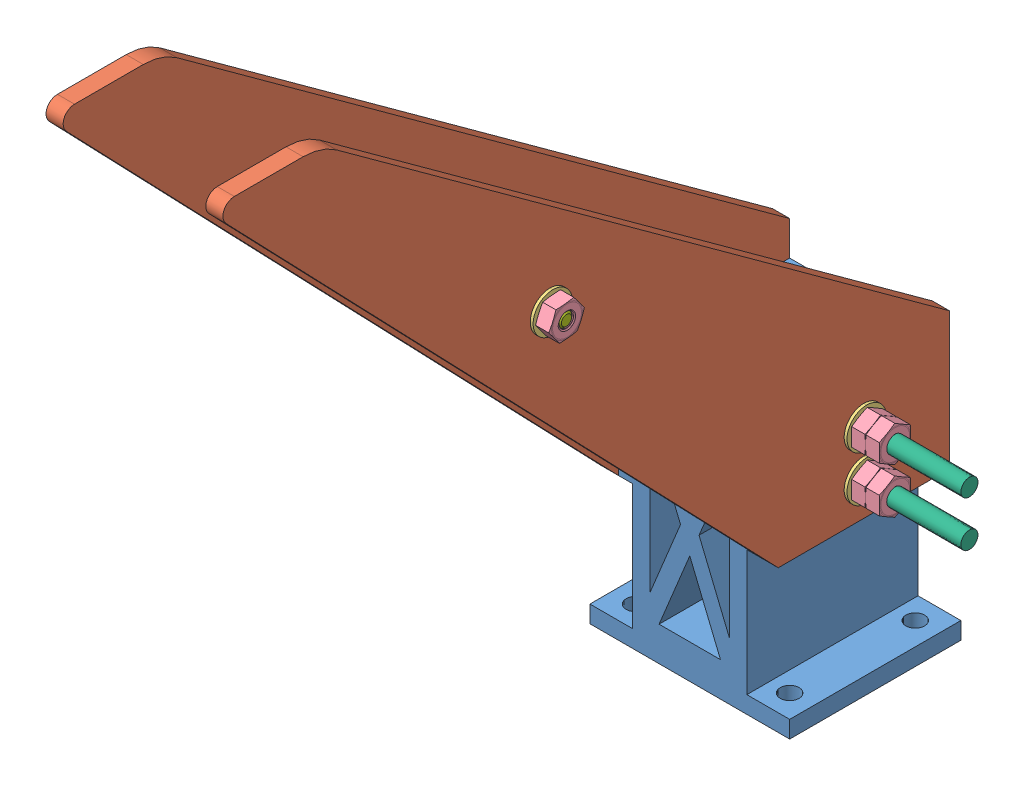
SolidWorks assembly landing gear, configuration Default. Lengths in mm.
Overall size (53 129 127.3).
18 component instances, 7 part files, 29 mates.
Components (placement in the parent):
- landing leg holder-1: landing leg holder [Default] at (5.6883 9.9646 36.397) size (35 43 30)
- landing leg plate-1: landing leg plate [Default] at (-8.3117 45.4646 36.397) x (0 -1 0) z (0 0 1) size (104 3 127.3)
- 9430100-1: 9430100 [Default] at (-10.3117 39.4646 36.397) x (0 -1 0) z (0 0 1) size (6.9 0.5 6.9)
- 9430100-2: 9430100 [Default] at (21.1883 39.4646 36.397) x (0 -1 0) z (0 0 1) size (6.9 0.5 6.9)
- 9430100-3: 9430100 [Default] at (21.1883 47.4646 36.397) x (0 -1 0) z (0 0 1) size (6.9 0.5 6.9)
- 9430100-4: 9430100 [Default] at (-10.3117 47.4646 36.397) x (0 -1 0) z (0 0 1) size (6.9 0.5 6.9)
- M3 Nut-1: M3 Nut [Default] at (25.6883 47.4646 36.397) x (0 0 -1) z (1 0 0) size (5.43 6.27 2.71)
- M3 Nut-2: M3 Nut [Default] at (20.1883 39.4646 36.397) x (0 0 1) z (-1 0 0) size (5.43 6.27 2.71)
- M3 Nut-3: M3 Nut [Default] at (22.6883 39.4646 36.397) x (0 0 1) z (-1 0 0) size (5.43 6.27 2.71)
- M3 Nut-4: M3 Nut [Default] at (22.6883 47.4646 36.397) x (0 0 1) z (-1 0 0) size (5.43 6.27 2.71)
- 9430100-5: 9430100 [Default] at (21.1883 92.4646 91.397) x (0 -1 0) z (0 0 1) size (6.9 0.5 6.9)
- 9430100-6: 9430100 [Default] at (-9.8117 92.4646 91.397) x (0 0.686928 -0.726726) z (0 0.726726 0.686928) size (6.9 0.5 6.9)
- M3x5-1: M3x5 [Default] at (-13.3117 92.4646 91.397) size (8 5.5 5.5)
- M3 Nut-5: M3 Nut [Default] at (20.1883 92.4646 91.397) x (0 -0.993661 -0.112418) z (-1 0 0) size (5.43 6.27 2.71)
- M3x50-1: M3x50 [Default] at (-13.3117 39.4646 36.397) size (53 5.5 5.5)
- M3x50-2: M3x50 [Default] at (-13.3117 47.4646 36.397) x (1 0 0) z (0 -0.610088 0.792334) size (53 5.5 5.5)
- M3 Spacer MF 25mm-1: M3 Spacer MF 25mm [Default] at (17.5844 92.4646 91.397) x (0 0 1) z (-1 0 0) size (5.24 4.54 31.5)
- landing leg plate-3: landing leg plate [Default] at (19.6883 45.4646 36.397) x (0 -1 0) z (0 0 1) size (104 3 127.3)
Mates (geometry in assembly coordinates):
- Coincident9: coincident anti-aligned: plane of 9430100-3 through (21.6883 47.4646 36.397) normal (1 0 0); plane of M3 Nut-1 through (21.6883 47.4646 36.397) normal (-1 0 0)
- Coincident10: coincident anti-aligned: plane of 9430100-2 through (21.6883 39.4646 36.397) normal (1 0 0); plane of M3 Nut-2 through (21.6883 39.4646 36.397) normal (-1 0 0)
- Coincident11: coincident anti-aligned: plane of M3 Nut-2 through (24.1883 39.4646 36.397) normal (1 0 0); plane of M3 Nut-3 through (24.1883 39.4646 36.397) normal (-1 0 0)
- Coincident12: coincident anti-aligned: plane of M3 Nut-1 through (24.1883 47.4646 36.397) normal (1 0 0); plane of M3 Nut-4 through (24.1883 47.4646 36.397) normal (-1 0 0)
- Coincident16: coincident anti-aligned: plane of 9430100-6 through (-10.3117 92.4646 91.397) normal (-1 0 0); plane of M3x5-1 through (-10.3117 93.9546 91.397) normal (1 0 0)
- Coincident17: coincident anti-aligned: plane of 9430100-5 through (21.6883 92.4646 91.397) normal (1 0 0); plane of M3 Nut-5 through (21.6883 92.4646 91.397) normal (-1 0 0)
- Coincident18: coincident anti-aligned: plane of 9430100-1 through (-10.3117 39.4646 36.397) normal (-1 0 0); plane of M3x50-1 through (-10.3117 40.9546 36.397) normal (1 0 0)
- Concentric22: concentric anti-aligned: circle of 9430100-2; cylinder of M3x50-1 through (39.6883 39.4646 36.397) axis (-1 0 0) radius 1.5
- Concentric23: concentric anti-aligned: circle of M3 Nut-2; cylinder of M3x50-1 through (39.6883 39.4646 36.397) axis (-1 0 0) radius 1.5
- Concentric24: concentric anti-aligned: circle of M3 Nut-3; cylinder of M3x50-1 through (39.6883 39.4646 36.397) axis (-1 0 0) radius 1.5
- Concentric26: concentric anti-aligned: cylinder of 9430100-1 through (-9.8117 39.4646 36.397) axis (1 0 0) radius 1.65; cylinder of M3x50-1 through (-102.0172 39.4646 36.397) axis (-1 0 0) radius 2.75
- Concentric27: concentric anti-aligned: cylinder of 9430100-3 through (21.1883 47.4646 36.397) axis (1 0 0) radius 3.45; circle of M3 Nut-1
- Concentric28: concentric aligned: cylinder of 9430100-3 through (21.1883 47.4646 36.397) axis (1 0 0) radius 3.45; circle of M3 Nut-4
- Concentric29: concentric anti-aligned: cylinder of 9430100-3 through (21.1883 47.4646 36.397) axis (1 0 0) radius 3.45; cylinder of M3x50-2 through (39.6883 47.4646 36.397) axis (-1 0 0) radius 1.5
- Coincident20: coincident anti-aligned: plane of 9430100-4 through (-10.3117 47.4646 36.397) normal (-1 0 0); plane of M3x50-2 through (-10.3117 48.6452 37.306) normal (1 0 0)
- Concentric35: concentric aligned: cylinder of 9430100-6 through (-9.8117 92.4646 91.397) axis (-1 0 0) radius 3.45; cylinder of M3x5-1 through (-102.0172 92.4646 91.397) axis (-1 0 0) radius 2.75
- Concentric50: concentric anti-aligned: cylinder of M3x5-1 through (-102.0172 92.4646 91.397) axis (-1 0 0) radius 2.75; cylinder of M3 Spacer MF 25mm-1 through (-7.4156 92.4646 91.397) axis (1 0 0) radius 1.5
- Coincident21: coincident anti-aligned: plane of landing leg holder-1 through (-6.8117 9.9646 36.397) normal (-1 0 0); plane of landing leg plate-1 through (-6.8117 45.4646 36.397) normal (1 0 0)
- Coincident22: coincident anti-aligned: plane of landing leg plate-1 through (-9.8117 45.4646 36.397) normal (-1 0 0); plane of 9430100-1 through (-9.8117 39.4646 36.397) normal (1 0 0)
- Concentric51: concentric aligned: cylinder of landing leg plate-1 through (-14.1958 39.4646 36.397) axis (1 0 0) radius 1.55; circle of M3x50-1
- Concentric52: concentric anti-aligned: cylinder of landing leg plate-1 through (-14.1958 47.4646 36.397) axis (1 0 0) radius 1.55; cylinder of M3x50-2 through (-102.0172 47.4646 36.397) axis (-1 0 0) radius 2.75
- Concentric53: concentric anti-aligned: cylinder of landing leg plate-1 through (-14.1958 92.4646 91.397) axis (1 0 0) radius 1.55; cylinder of M3x5-1 through (-102.0172 92.4646 91.397) axis (-1 0 0) radius 2.75
- Coincident23: coincident anti-aligned: plane of landing leg plate-1 through (-9.8117 45.4646 36.397) normal (-1 0 0); plane of 9430100-6 through (-9.8117 92.4646 91.397) normal (1 0 0)
- Concentric54: concentric anti-aligned: circle of 9430100-5; cylinder of M3 Spacer MF 25mm-1 through (24.0844 92.4646 91.397) axis (-1 0 0) radius 1.5
- Concentric55: concentric aligned: cylinder of 9430100-5 through (21.1883 92.4646 91.397) axis (1 0 0) radius 3.45; circle of M3 Nut-5
- Concentric58: concentric anti-aligned: cylinder of 9430100-4 through (-10.3117 47.4646 36.397) axis (1 0 0) radius 3.45; cylinder of M3x50-2 through (-102.0172 47.4646 36.397) axis (-1 0 0) radius 2.75
- Coincident24: coincident anti-aligned: plane of landing leg plate-1 through (-9.8117 45.4646 36.397) normal (-1 0 0); plane of 9430100-4 through (-9.8117 47.4646 36.397) normal (1 0 0)
- Concentric59: concentric aligned: cylinder of landing leg holder-1 through (22.8552 39.4646 36.397) axis (-1 0 0) radius 1.65; cylinder of M3x50-1 through (-102.0172 39.4646 36.397) axis (-1 0 0) radius 2.75
- Concentric62: concentric aligned: cylinder of landing leg holder-1 through (22.8552 47.4646 36.397) axis (-1 0 0) radius 1.65; cylinder of M3x50-2 through (-102.0172 47.4646 36.397) axis (-1 0 0) radius 2.75
